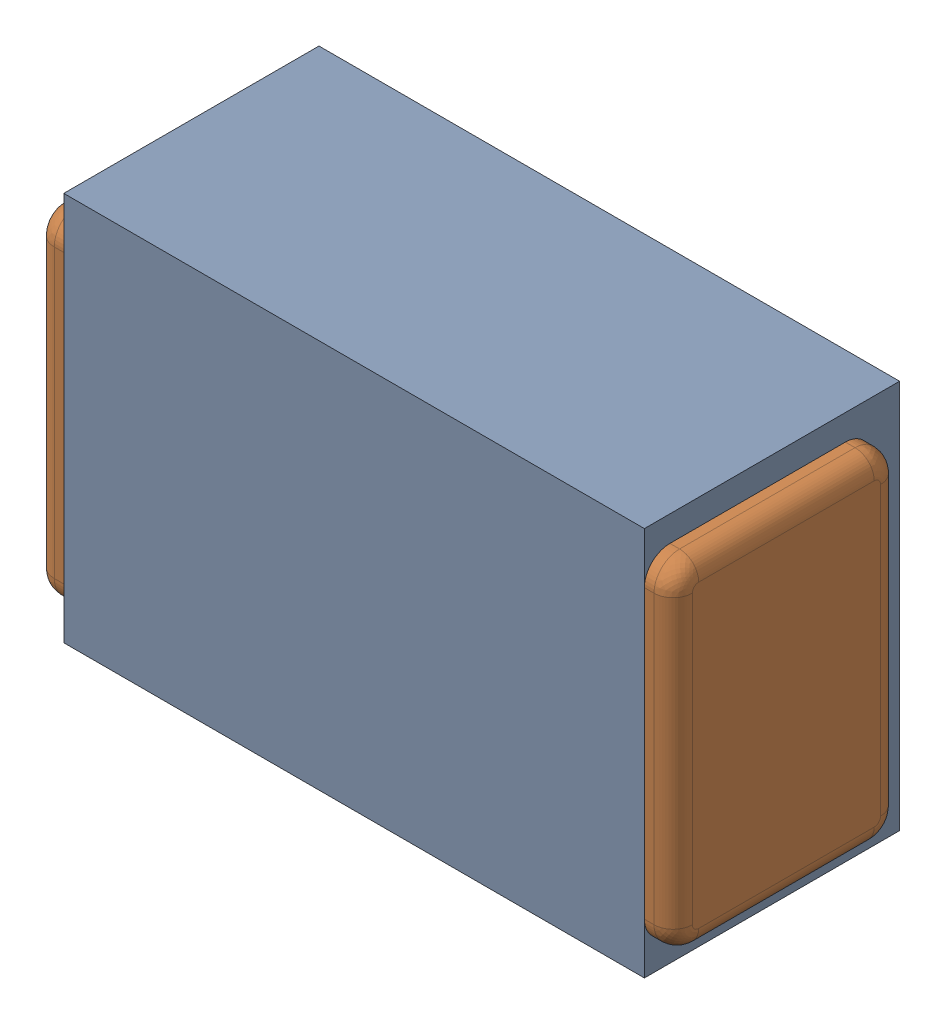
SolidWorks assembly C47, configuration Default. Lengths in mm.
Overall size (1 0.61 0.4).
3 component instances, 2 part files, 0 mates.
Components (placement in the parent):
- 1088880352-1: 1088880352 [Default] at (10.875 1.4 -2.044) size (0.91 0.61 0.4)
  - Extruded-28-1: Extruded-28 [Default] at origin size (0.91 0.61 0.4)
- C0402-1: C0402 [Default] at (10.8751 1.3999 -1.644) x (1 0 0) z (0 1 0) size (1 0.36 0.54)
